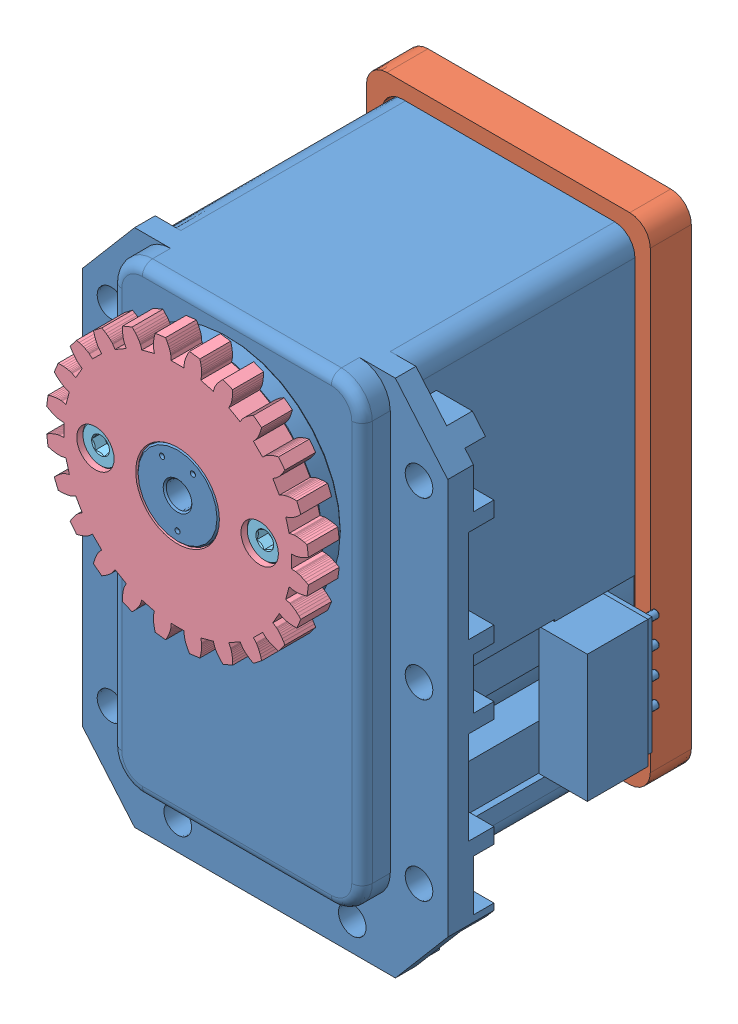
SolidWorks assembly block_actuator_gear_o, configuration Default. Lengths in mm.
Overall size (35.6 52.23 39.77).
9 component instances, 5 part files, 18 mates.
Components (placement in the parent):
- dynamixel MX-28-exposed-1: dynamixel MX-28-exposed [Back Off] at origin size (35.6 50.6 39.77)
- d2_o-1: d2_o [Default] at (-12.375 -33.125 -8.75) x (0 1 0) z (0 0 -1) size (48.25 27.65 4)
- 91772A266 2-56 L5-4 pan-1: 91772A266 2-56 L5-4 pan [91772A266] at (-9.3 9 12.65) x (-0.205276 0.978704 0) z (0 0 -1) size (4.24 4.24 27.06)
- 91772A266 2-56 L5-4 pan-2: 91772A266 2-56 L5-4 pan [91772A266] at (9.2 9 12.65) x (-0.795891 0.60544 0) z (0 0 -1) size (4.24 4.24 27.06)
- 91772A266 2-56 L5-4 pan-3: 91772A266 2-56 L5-4 pan [91772A266] at (9.2 -30 12.65) x (-0.25415 0.967165 0) z (0 0 -1) size (4.24 4.24 27.06)
- 91772A266 2-56 L5-4 pan-4: 91772A266 2-56 L5-4 pan [91772A266] at (-9.3 -30 12.65) x (-0.098208 -0.995166 0) z (0 0 -1) size (4.24 4.24 27.06)
- b2_o-1: b2_o [Default] at (0 0 20.52) size (25.49 25.49 3)
- 91292A003 M2 L3 socket-1: 91292A003 M2 L3 socket [91292A003] at (-8 0 18.02) x (-0.923728 -0.383049 0) z (0 0 -1) size (3.8 3.8 5.09)
- 91292A003 M2 L3 socket-2: 91292A003 M2 L3 socket [91292A003] at (8 0 18.02) x (-0.577343 -0.816502 0) z (0 0 -1) size (3.8 3.8 5.09)
Mates (geometry in assembly coordinates):
- Concentric2: concentric anti-aligned: cylinder of dynamixel MX-28-exposed-1 through (9.2 9 1.25) axis (0 0 -1) radius 1.15; cylinder of d2_o-1 through (9.2 9 -13.1906) axis (0 0 1) radius 1.075
- Parallel1: parallel aligned: plane of dynamixel MX-28-exposed-1 through (12.2 12 -17.75) normal (0 1 0); plane of d2_o-1 through (-13.875 13.625 -12.75) normal (0 1 0)
- Coincident2: coincident anti-aligned: plane of dynamixel MX-28-exposed-1 through (-10.2 -31 -8.75) normal (0 0 -1); plane of d2_o-1 through (-12.375 -33.125 -8.75) normal (0 0 1)
- Concentric4: concentric anti-aligned: cylinder of d2_o-1 through (-9.3 9 -13.1906) axis (0 0 1) radius 1.075; circle of 91772A266 2-56 L5-4 pan-1
- Coincident3: coincident anti-aligned: plane of d2_o-1 through (-12.375 -33.125 -12.75) normal (0 0 -1); plane of 91772A266 2-56 L5-4 pan-1 through (-9.3 9 -12.75) normal (0 0 1)
- Concentric5: concentric anti-aligned: cylinder of d2_o-1 through (9.2 9 -13.1906) axis (0 0 1) radius 1.075; circle of 91772A266 2-56 L5-4 pan-2
- Coincident4: coincident anti-aligned: plane of d2_o-1 through (-12.375 -33.125 -12.75) normal (0 0 -1); plane of 91772A266 2-56 L5-4 pan-2 through (9.2 9 -12.75) normal (0 0 1)
- Concentric6: concentric anti-aligned: cylinder of d2_o-1 through (9.2 -30 -13.1906) axis (0 0 1) radius 1.075; circle of 91772A266 2-56 L5-4 pan-3
- Coincident5: coincident aligned: plane of d2_o-1 through (-12.375 -33.125 -12.75) normal (0 0 -1); circle of 91772A266 2-56 L5-4 pan-3
- Concentric7: concentric anti-aligned: cylinder of d2_o-1 through (-9.3 -30 -13.1906) axis (0 0 1) radius 1.075; circle of 91772A266 2-56 L5-4 pan-4
- Coincident6: coincident anti-aligned: plane of d2_o-1 through (-12.375 -33.125 -12.75) normal (0 0 -1); plane of 91772A266 2-56 L5-4 pan-4 through (-9.3 -30 -12.75) normal (0 0 1)
- Concentric13: concentric anti-aligned: cylinder of dynamixel MX-28-exposed-1 through (0 0 37.8337) axis (0 0 -1) radius 4; cylinder of b2_o-1 through (0 0 20.52) axis (0 0 1) radius 4.075
- Coincident11: coincident anti-aligned: plane of dynamixel MX-28-exposed-1 through (0 0 20.52) normal (0 0 1); plane of b2_o-1 through (0 0 20.52) normal (0 0 -1)
- Concentric14: concentric aligned: cylinder of dynamixel MX-28-exposed-1 through (-8 0 -19.251) axis (0 0 1) radius 0.9; cylinder of b2_o-1 through (-8 0 21.02) axis (0 0 1) radius 1.825
- Concentric15: concentric anti-aligned: cylinder of b2_o-1 through (-8 0 21.02) axis (0 0 1) radius 1.825; cylinder of 91292A003 M2 L3 socket-1 through (-8 0 23.02) axis (0 0 -1) radius 1.9
- Coincident12: coincident anti-aligned: plane of b2_o-1 through (-8 0 21.02) normal (0 0 1); plane of 91292A003 M2 L3 socket-1 through (-8 0 21.02) normal (0 0 -1)
- Concentric16: concentric anti-aligned: cylinder of b2_o-1 through (8 0 21.02) axis (0 0 1) radius 1.825; cylinder of 91292A003 M2 L3 socket-2 through (8 0 23.02) axis (0 0 -1) radius 1.9
- Coincident13: coincident anti-aligned: plane of b2_o-1 through (8 0 21.02) normal (0 0 1); plane of 91292A003 M2 L3 socket-2 through (8 0 21.02) normal (0 0 -1)
